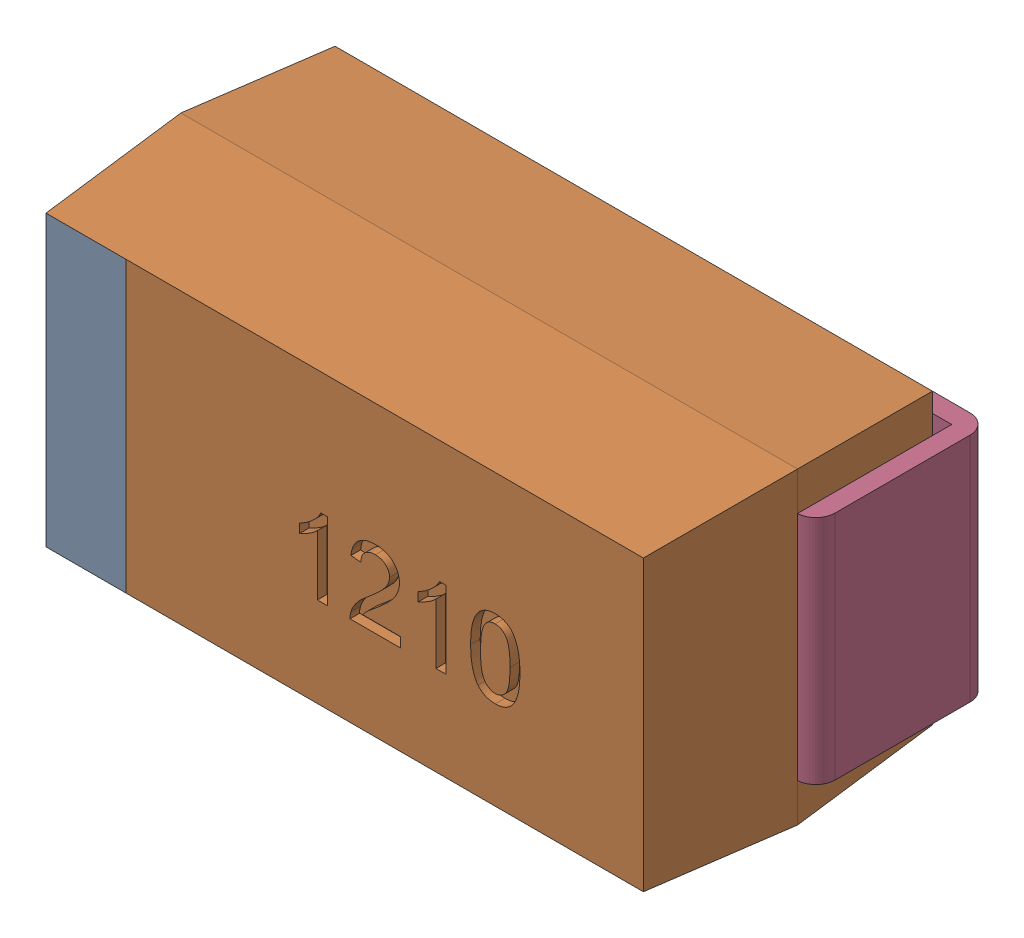
SolidWorks assembly User_Library-Tantalum_Capacitor_Case_A, configuration Default. Lengths in mm.
Overall size (3.39 1.6 1.65).
3 component instances, 2 part files, 0 mates.
Components (placement in the parent):
- User_Library-Tantalum_Capacitor_Case_A_Tantalum_case_A_part1-1: User_Library-Tantalum_Capacitor_Case_A_Tantalum_case_A_part1 [Default] at (-1.5973 -0.8 0.1) size (3.2 1.6 1.6)
- User_Library-Tantalum_Capacitor_Case_A_Tantalum_case_A_part2-1: User_Library-Tantalum_Capacitor_Case_A_Tantalum_case_A_part2 [Default] at (-0.8925 -0.6 0.05) x (-1 0 0) z (0 0 -1) size (0.8 1.2 0.9)
- User_Library-Tantalum_Capacitor_Case_A_Tantalum_case_A_part2-2: User_Library-Tantalum_Capacitor_Case_A_Tantalum_case_A_part2 [Default] at (0.8979 0.6 0.05) x (1 0 0) z (0 0 -1) size (0.8 1.2 0.9)
